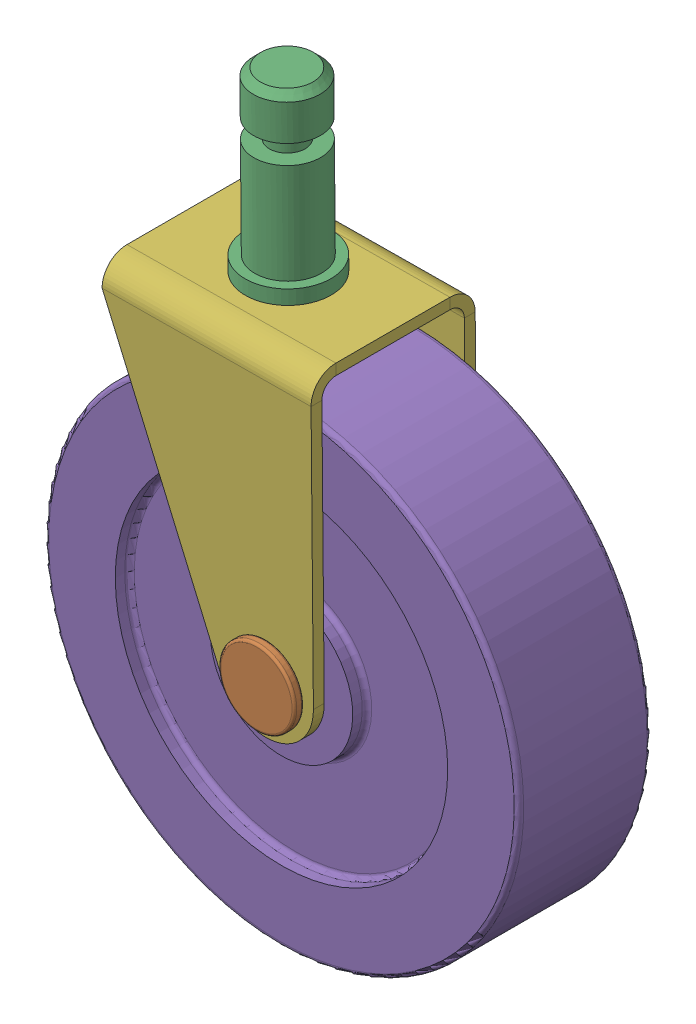
SolidWorks assembly Caster_wheel_model, configuration Default. Lengths in mm.
Overall size (137.52 166.04 40).
6 component instances, 6 part files, 10 mates.
Components (placement in the parent):
- 3.Bush-1: 3.Bush [Default] at (-22.3109 20.6777 20.1745) size (14 14 28)
- 4.Bolt-1: 4.Bolt [Default] at (-22.3109 20.6777 39.4525) x (0 0 -1) z (0.982543 0.186037 0) size (40 16 16)
- 5.Post-1: 5.Post [Default] at (-30.0202 74.8889 15.0568) x (-0.682236 -0.006101 0.731106) z (-0.731077 -0.006538 -0.682263) size (18 43 18)
- 6.circlip-1: 6.circlip [Default] at (-22.3109 20.6777 2.0875) x (1 0 0) z (0 -1 0) size (9.65 0.64 8.98)
- Caster_wheel_base-1: Caster_wheel_base [Default] at (-22.3109 20.6777 20.1745) x (0 0 1) z (-0.522769 -0.852474 0) size (28 100 100)
- Frame-1: Frame [Default] at (-34.221 10.5708 20.1745) x (0 0 -1) z (0.99996 0.008943 0) size (34.56 70.28 44)
Mates (geometry in assembly coordinates):
- Width1: width anti-aligned: plane of Caster_wheel_base-1 through (-28.2782 24.3371 6.1745) normal (0 0 -1); plane of Caster_wheel_base-1 through (-28.2782 24.3371 34.1745) normal (0 0 1); plane of 3.Bush-1 through (-22.3109 20.6777 34.1745) normal (0 0 1); plane of 3.Bush-1 through (-22.3109 20.6777 6.1745) normal (0 0 -1)
- Concentric1: concentric aligned: cylinder of 3.Bush-1 through (-22.3109 20.6777 34.1745) axis (0 0 -1) radius 7; cylinder of Caster_wheel_base-1 through (-22.3109 20.6777 20.1745) axis (0 0 -1) radius 7
- Width2: width anti-aligned: plane of Caster_wheel_base-1 through (-52.1475 38.9746 9.1745) normal (0 0 -1); plane of Caster_wheel_base-1 through (-52.1475 38.9746 31.1745) normal (0 0 1); plane of Frame-1 through (-12.2219 10.7675 5.1745) normal (0 0 1); plane of Frame-1 through (-12.2219 10.7675 35.1745) normal (0 0 -1)
- Concentric2: concentric aligned: cylinder of 3.Bush-1 through (-22.3109 20.6777 34.1745) axis (0 0 -1) radius 4; cylinder of Frame-1 through (-22.3109 20.6777 37.4525) axis (0 0 -1) radius 4
- Coincident1: coincident anti-aligned: plane of 4.Bolt-1 through (-23.0086 24.3622 37.4525) normal (0 0 -1); plane of Frame-1 through (-12.2219 10.7675 37.4525) normal (0 0 1)
- Concentric3: concentric anti-aligned: cylinder of 3.Bush-1 through (-22.3109 20.6777 34.1745) axis (0 0 -1) radius 4; cylinder of 4.Bolt-1 through (-22.3109 20.6777 39.4525) axis (0 0 1) radius 3.75
- Width4: width anti-aligned: plane of 4.Bolt-1 through (-23.0086 24.3622 2.4525) normal (0 0 -1); plane of 4.Bolt-1 through (-22.9062 23.8218 1.7225) normal (0 0 1); plane of 6.circlip-1 through (-22.3109 20.6777 2.405) normal (0 0 1); plane of 6.circlip-1 through (-22.3109 20.6777 1.77) normal (0 0 -1)
- Concentric6: concentric anti-aligned: cylinder of 4.Bolt-1 through (-22.3109 20.6777 39.4525) axis (0 0 1) radius 3.2; cylinder of 6.circlip-1 through (-22.3109 20.6777 2.405) axis (0 0 -1) radius 3.175
- Concentric7: concentric aligned: cylinder of 5.Post-1 through (-35.1804 117.8445 20.1745) axis (-0.008943 0.99996 0) radius 7; cylinder of Frame-1 through (-34.221 10.5708 20.1745) axis (-0.008943 0.99996 0) radius 7.25
- Coincident2: coincident anti-aligned: plane of 5.Post-1 through (-30.0738 80.8887 15.0568) normal (0.008943 -0.99996 0); plane of Frame-1 through (-12.8504 81.0427 5.1745) normal (-0.008943 0.99996 0)
